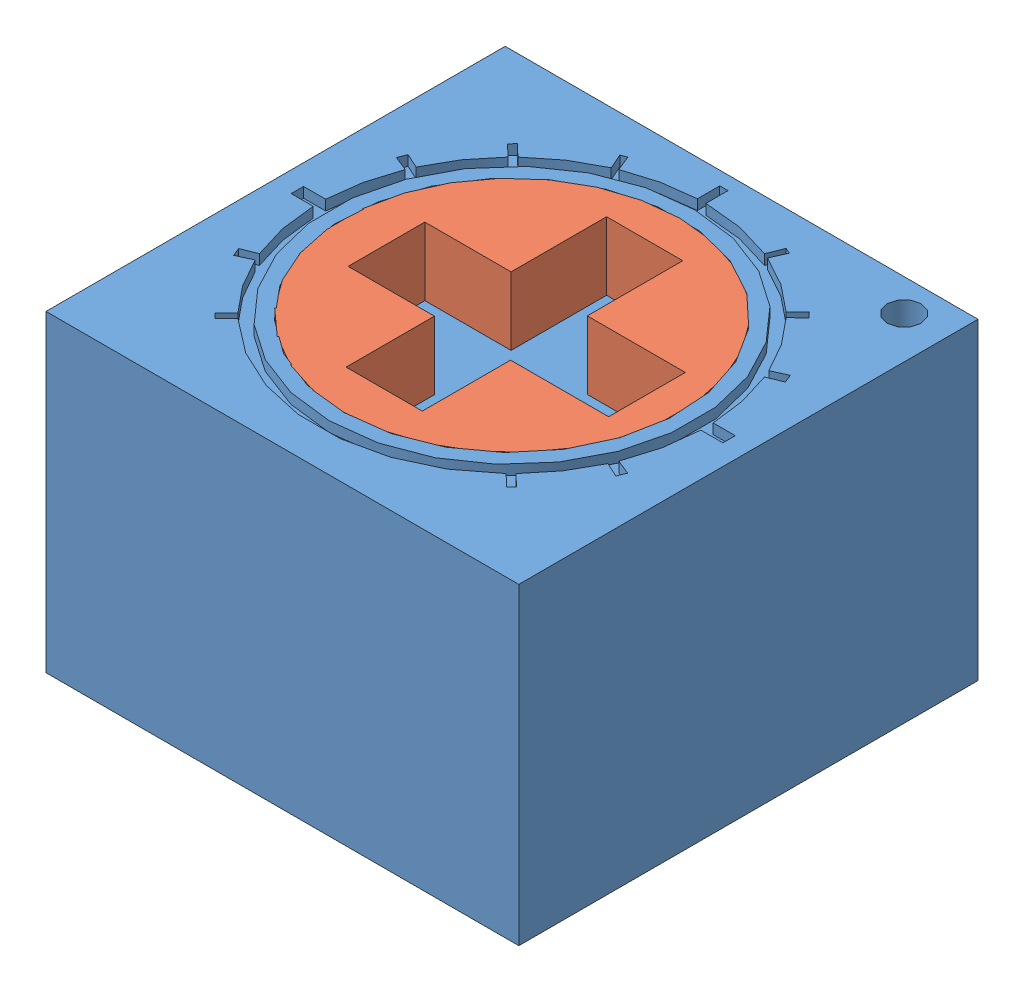
SolidWorks assembly vise, configuration Default. Lengths in mm.
Overall size (6.95 4.6 6.75).
2 component instances, 2 part files, 1 mates.
Components (placement in the parent):
- support vise-1: support vise [Default] at (5.2033 1.0932 9.3254) size (6.95 4.6 6.75)
- cercle vise-2: cercle vise [Default] at (1.7283 4.6932 5.9504) size (4.94 1 4.94)
Mates (geometry in assembly coordinates):
- Concentric1: concentric aligned: circle of support vise-1; circle of cercle vise-2
